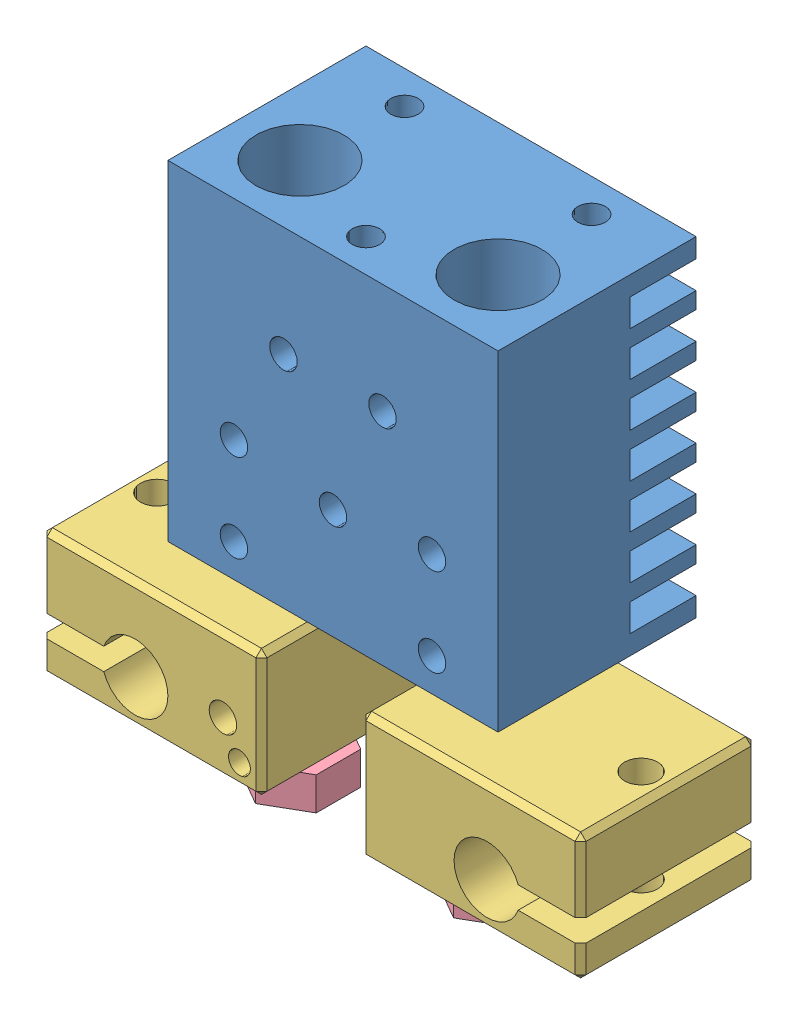
SolidWorks assembly E3D chimera, configuration Default. Lengths in mm.
Overall size (49 50.6 20).
7 component instances, 4 part files, 13 mates.
Components (placement in the parent):
- heat sink-1: heat sink [Default] at (5.509 2.1803 24.9939) size (30 30 18)
- heat break-1: heat break [Default] at (-3.491 -5.9197 27.9939) size (6.9 21.1 6.9)
- heat break-2: heat break [Default] at (14.509 -5.9197 27.9939) x (0.999995 0 -0.003239) z (0.003239 0 0.999995) size (6.9 21.1 6.9)
- heater block-1: heater block [Default] at (20.009 -11.9197 27.9939) x (-1 0 0) z (0 0 -1) size (20 11.5 16)
- heater block-2: heater block [Default] at (-8.991 -11.9738 27.9939) size (20 11.5 16)
- 0.4 nozzle-1: 0.4 nozzle [Default] at (14.509 -18.4197 27.9939) size (7 12.5 8.08)
- 0.4 nozzle-2: 0.4 nozzle [Default] at (-3.491 -18.4197 27.9939) size (7 12.5 8.08)
Mates (geometry in assembly coordinates):
- Concentric1: concentric aligned: cylinder of heat sink-1 through (14.509 16.1803 27.9939) axis (0 -1 0) radius 3.45; cylinder of heat break-2 through (14.509 -5.9197 27.9939) axis (0 -1 0) radius 3.45
- Coincident1: coincident aligned: plane of heat sink-1 through (5.509 2.1803 24.9939) normal (0 -1 0); plane of heat break-2 through (13.034 2.1803 27.9987) normal (0 -1 0)
- Coincident2: coincident aligned: plane of heat sink-1 through (5.509 2.1803 24.9939) normal (0 -1 0); plane of heat break-1 through (-4.966 2.1803 27.9939) normal (0 -1 0)
- Concentric2: concentric aligned: cylinder of heat sink-1 through (-3.491 16.1803 27.9939) axis (0 -1 0) radius 3.45; cylinder of heat break-1 through (-3.491 -5.9197 27.9939) axis (0 -1 0) radius 3.45
- Concentric3: concentric aligned: cylinder of heat break-1 through (-3.491 -5.9197 27.9939) axis (0 -1 0) radius 3; cylinder of heater block-2 through (-3.491 -0.4738 27.9939) axis (0 -1 0) radius 3
- Concentric4: concentric aligned: cylinder of heat break-2 through (14.509 -5.9197 27.9939) axis (0 -1 0) radius 3; cylinder of heater block-1 through (14.509 -0.4197 27.9939) axis (0 -1 0) radius 3
- Coincident3: coincident aligned: plane of heat break-2 through (11.509 -0.4197 28.0036) normal (0 1 0); plane of heater block-1 through (20.009 -0.4197 27.9939) normal (0 1 0)
- Concentric5: concentric aligned: cylinder of heater block-1 through (14.509 -0.4197 27.9939) axis (0 -1 0) radius 3; cylinder of 0.4 nozzle-1 through (14.509 -18.4197 27.9939) axis (0 -1 0) radius 3
- Coincident6: coincident anti-aligned: plane of heat break-2 through (13.509 -5.9197 27.9971) normal (0 -1 0); plane of 0.4 nozzle-1 through (14.509 -5.9197 27.9939) normal (0 1 0)
- Concentric6: concentric aligned: cylinder of heater block-2 through (-3.491 -0.4738 27.9939) axis (0 -1 0) radius 3; cylinder of 0.4 nozzle-2 through (-3.491 -18.4197 27.9939) axis (0 -1 0) radius 3
- Coincident7: coincident anti-aligned: plane of heat break-1 through (-4.491 -5.9197 27.9939) normal (0 -1 0); plane of 0.4 nozzle-2 through (-3.491 -5.9197 27.9939) normal (0 1 0)
- Parallel1: parallel aligned: plane of heat sink-1 through (20.509 32.1803 33.9939) normal (0 0 1); plane of heater block-1 through (10.009 -0.4197 35.9939) normal (0 0 1)
- Parallel2: parallel aligned: plane of heat sink-1 through (20.509 32.1803 33.9939) normal (0 0 1); plane of heater block-2 through (1.009 -0.4738 35.9939) normal (0 0 1)
